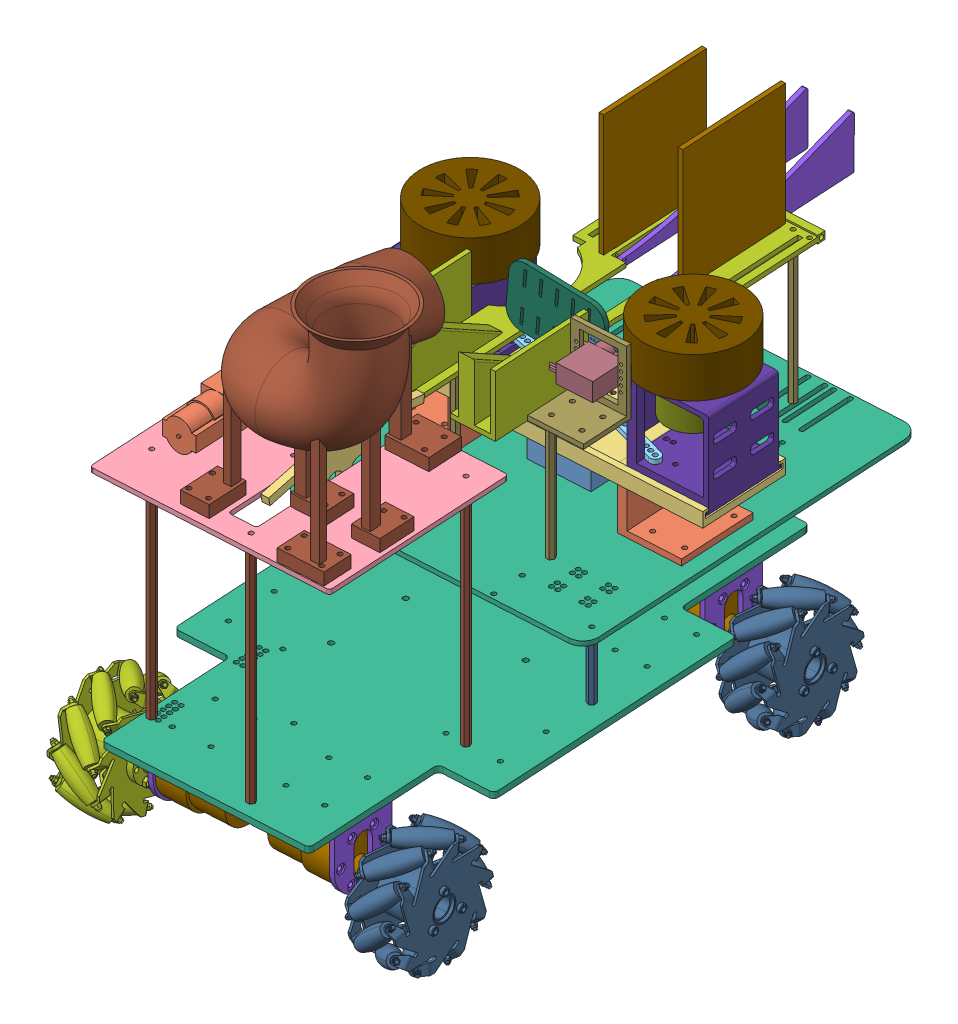
SolidWorks assembly 方案2完整, configuration 默认. Lengths in mm.
Overall size (245.27 390.99 446.91).
58 component instances, 32 part files, 89 mates.
Components (placement in the parent):
- 30kg大舵机-1: 30kg大舵机 [默认] at (-146.1932 -42.7359 104.9499) x (0.998416 0 -0.056268) z (0.056268 0 0.998416) size (54.5 44.5 20)
- 舵机固定架-1: 舵机固定架 [默认] at (-145.3492 -44.2359 119.9261) x (0.998416 0 -0.056268) z (0.056268 0 0.998416) size (180 36 50)
- 摩擦轮轨道-1: 摩擦轮轨道 [默认] at (-219.81 -12.6559 99.0829) x (0.998416 0 -0.056268) z (0.056268 0 0.998416) size (200 9.5 58)
- 摩擦轮传动舵盘-1: 摩擦轮传动舵盘 [默认] at (-135.444 -1.7359 94.3282) x (0.98502 0 0.17244) z (0 1 0) size (47 9.88 7.5)
- 摩擦轮传动杆-1: 摩擦轮传动杆 [默认] at (-175.5138 3.2641 86.9233) x (0.981614 0 0.190879) z (0 -1 0) size (48 7 3)
- 摩擦轮传动杆-2: 摩擦轮传动杆 [默认] at (-99.8398 3.2641 102.168) x (-0.963541 0 -0.26756) z (0 -1 0) size (48 7 3)
- 底板-麦轮装配体-1: 底板-麦轮装配体 [默认] at (149.5944 -56.9718 163.5191) x (0.056268 0 0.998416) z (-0.998416 0 0.056268) size (360.68 101.49 223.34)
  - 车底板-1: 车底板 [默认] at (-4.9651 -34.2642 350) size (350 4 200)
  - 75mecanumzuo-4: 75mecanumzuo [默认] at (-125.1754 -68.2642 364.1942) x (0.997346 -0.072807 0) z (-0.072807 -0.997346 0) size (77.38 50.5 75.94)
  - 电机支架-7: 电机支架 [默认] at (-145.2754 -37.4642 343.8942) x (1 0 0) z (0 1 0) size (40.2 43 47)
  - 新电机-1: 新电机 [默认] at (-125.1754 -61.2642 298.9942) x (-1 0 0) z (0 0 1) size (37 37 66.7)
  - 新电机-2: 新电机 [默认] at (-124.8754 -61.2642 272.0527) x (1 0 0) z (0 0 -1) size (37 37 66.7)
  - 电机支架-8: 电机支架 [默认] at (-104.7754 -37.4642 227.1527) x (-1 0 0) z (0 1 0) size (40.2 43 47)
  - 75mecanumyou-3: 75mecanumyou [默认] at (-124.8754 -68.2642 206.8527) x (0.923728 0.383049 0) z (-0.383049 0.923728 0) size (77.38 50.5 77.78)
  - 75mecanumzuo-6: 75mecanumzuo [默认] at (134.2366 -68.2642 364.1942) x (0.997346 -0.072807 0) z (-0.072807 -0.997346 0) size (77.38 50.5 75.94)
  - 新电机-3: 新电机 [默认] at (134.2366 -61.2642 298.9942) x (-1 0 0) z (0 0 1) size (37 37 66.7)
  - 电机支架-9: 电机支架 [默认] at (114.1366 -37.4642 343.8942) x (1 0 0) z (0 1 0) size (40.2 43 47)
  - 新电机-4: 新电机 [默认] at (134.5366 -61.2642 272.0527) x (1 0 0) z (0 0 -1) size (37 37 66.7)
  - 电机支架-10: 电机支架 [默认] at (154.6366 -37.4642 227.1527) x (-1 0 0) z (0 1 0) size (40.2 43 47)
  - 75mecanumyou-4: 75mecanumyou [默认] at (134.5366 -68.2642 206.8527) x (0.923728 0.383049 0) z (-0.383049 0.923728 0) size (77.38 50.5 77.78)
- 储弹管道-1: 储弹管道 [默认] at (-55.5513 137.7641 176.0746) x (0.056268 0 0.998416) z (-0.998416 0 0.056268) size (367.8 225.29 130.07)
- 40mm乒乓球-1: 40mm乒乓球 [默认] at (274.1004 235.7665 253.765) size (40 40 40) (hidden)
- 68mm网球-1: 68mm网球 [默认] at (387.195 229.0328 158.137) size (68 68 68) (hidden)
- mg90s舵机架-1: mg90s舵机架 [默认] at (-96.1146 50.7641 144.5432) x (-0.056268 0 -0.998416) z (0.998416 0 -0.056268) size (33 43 35)
- mg90s舵机-1: mg90s舵机 [默认] at (-78.164 79.6974 152.045) x (-0.998416 0 0.056268) z (0 -1 0) size (37.5 29 12)
- MG90S舵机臂-1: MG90S舵机臂 [默认] at (-84.8651 73.6974 130.8886) x (-0.994686 0.086351 0.056058) z (0.056268 0 0.998416) size (22 6.06 4)
- 弹道挡板-1: 弹道挡板 [默认] at (-118.7266 76.6334 132.0457) x (0.994686 -0.086351 -0.056058) z (-0.086214 -0.996265 0.004859) size (60 3 40)
- 3525电机和摩擦轮-1: 3525电机和摩擦轮 [默认] at (-175.4048 30.8362 96.7355) x (0 -1 0) z (-0.998416 0 0.056268) size (87.12 88.79 88.79)
  - 3525电机-1: 3525电机 [默认] at (4.9249 -1.155 36.6) size (36.6 35.3 35.3)
  - 3525电机固定支架-1: 3525电机固定支架 [默认] at (-17.4279 -1.155 36.6) x (0 -1 0) z (1 0 0) size (53 51 56.22)
  - 蓝色摩擦轮-1: 蓝色摩擦轮 [默认] at (-48.33 -1.155 36.6) x (0 -0.866025 -0.5) z (0 -0.5 0.866025) size (65 26.5 65)
  - 六角联轴器-1: 六角联轴器 [默认] at (-19.83 -1.155 36.6) x (0 0 1) z (-1 0 0) size (14 12.12 17)
- 3525电机和摩擦轮-2: 3525电机和摩擦轮 [默认] at (-108.5094 30.8362 91.6534) x (0 -1 0) z (0.998416 0 -0.056268) size (87.12 88.79 88.79)
  - 3525电机-1: 3525电机 [默认] at (4.9249 -1.155 36.6) size (36.6 35.3 35.3)
  - 3525电机固定支架-1: 3525电机固定支架 [默认] at (-17.4279 -1.155 36.6) x (0 -1 0) z (1 0 0) size (53 51 56.22)
  - 蓝色摩擦轮-1: 蓝色摩擦轮 [默认] at (-48.33 -1.155 36.6) x (0 -0.866025 -0.5) z (0 -0.5 0.866025) size (65 26.5 65)
  - 六角联轴器-1: 六角联轴器 [默认] at (-19.83 -1.155 36.6) x (0 0 1) z (-1 0 0) size (14 12.12 17)
- tt电机-1: tt电机 [默认] at (-178.7459 76.9141 263.1303) x (0 1 0) z (0.998416 0 -0.056268) size (22.3 70 34.8)
- 螺旋桨-1: 螺旋桨 [默认] at (-120.3207 76.9141 270.8551) x (-0.050533 0.439834 -0.896656) z (-0.998416 0 0.056268) size (108.77 108.8 23.05)
- 管道固定底板-1: 管道固定底板 [默认] at (-121.0819 65.7641 276.2549) x (0.056268 0 0.998416) z (0 -1 0) size (125 150 3)
- 5-5圆柱轴承-1: 5-5圆柱轴承 [默认] at (-167.8912 76.9141 273.536) x (0.005277 -0.995593 0.093626) z (0.05602 0.093775 0.994016) size (14 22 14)
- 弹射装置固定板-1: 弹射装置固定板 [默认] at (-142.9079 -47.2359 82.4057) x (-0.056268 0 -0.998416) z (0 1 0) size (234.46 189.43 3)
- 出射轨道底板可加挡板-1: 出射轨道底板可加挡板 [默认] at (-135.5775 50.7641 119.6712) x (-0.056268 0 -0.998416) z (0.998416 0 -0.056268) size (235.25 48.86 188.9)
- 出射斜面1-1: 出射斜面1 [默认] at (-157.0188 48.7368 23.5714) x (-0.056268 -0.00087 -0.998415) z (0.998416 0 -0.056268) size (130 34.64 3)
- 出射斜面1-2: 出射斜面1 [默认] at (-128.0648 48.7368 21.9396) x (-0.056268 -0.00087 -0.998415) z (0.998416 0 -0.056268) size (130 34.64 3)
- 出射挡板-1: 出射挡板 [默认] at (-165.6361 68.2924 25.2837) x (-0.056268 0 -0.998416) z (0.998416 0 -0.056268) size (72 87 3)
- 出射挡板-2: 出射挡板 [默认] at (-116.7176 68.2924 18.9045) x (0.056268 0 0.998416) z (-0.998416 0 0.056268) size (72 87 3)
- M3铜柱（40）-1: M3铜柱（40） [默认] at (-220.0987 -87.2359 188.6845) x (0.96885 0 0.24765) z (-0.24765 0 0.96885) size (5.3 40 4.7)
- M3铜柱（40）-2: M3铜柱（40） [默认] at (-190.9009 -87.2359 42.461) x (0.96885 0 0.24765) z (-0.24765 0 0.96885) size (5.3 40 4.7)
- M3铜柱（40）-3: M3铜柱（40） [默认] at (-103.7976 -87.2359 37.5521) x (0.96885 0 0.24765) z (-0.24765 0 0.96885) size (5.3 40 4.7)
- M3铜柱（40）-4: M3铜柱（40） [默认] at (-50.368 -87.2359 179.1189) x (0.926987 0 0.375094) z (-0.375094 0 0.926987) size (5.3 40 4.7)
- M3铜柱（150)-1: M3铜柱（150) [默认] at (-106.1404 -87.2359 347.8816) size (5.3 150 4.7)
- M3铜柱（150)-2: M3铜柱（150) [默认] at (-67.8932 -87.2359 244.5658) x (0.997575 0 0.069601) z (-0.069601 0 0.997575) size (5.3 150 4.7)
- M3铜柱（150)-3: M3铜柱（150) [默认] at (-186.9352 -87.2359 332.6537) x (0.999953 0 0.009678) z (-0.009678 0 0.999953) size (5.3 150 4.7)
- M3铜柱（95）-1: M3铜柱（95） [默认] at (-103.8085 -44.2359 152.7028) size (5.3 95 4.7)
- M3铜柱（95）-2: M3铜柱（95） [默认] at (-163.434 -44.2359 156.0631) x (0.94331 0 -0.331914) z (0.331914 0 0.94331) size (5.3 95 4.7)
- M3铜柱（95）-3: M3铜柱（95） [默认] at (-112.979 -44.2359 -16.1108) x (0.94331 0 -0.331914) z (0.331914 0 0.94331) size (5.3 95 4.7)
- M3铜柱（95）-4: M3铜柱（95） [默认] at (-173.2891 -44.2359 -12.7119) x (0.94331 0 -0.331914) z (0.331914 0 0.94331) size (5.3 95 4.7)
Mates (geometry in assembly coordinates):
- 同心1: concentric aligned: cylinder of 30kg大舵机-1 through (-171.758 -32.2359 91.3668) axis (0 1 0) radius 2.5; cylinder of 舵机固定架-1 through (-171.758 -44.2359 91.3668) axis (0 1 0) radius 2.5
- 同心2: concentric aligned: cylinder of 30kg大舵机-1 through (-171.1953 -32.2359 101.351) axis (0 1 0) radius 2.5; cylinder of 舵机固定架-1 through (-171.1953 -44.2359 101.351) axis (0 1 0) radius 2.5
- 同心5: concentric aligned: cylinder of 30kg大舵机-1 through (-122.3165 -32.2359 88.5804) axis (0 1 0) radius 2.5; cylinder of 舵机固定架-1 through (-122.3165 -44.2359 88.5804) axis (0 1 0) radius 2.5
- 重合3: coincident anti-aligned: plane of 30kg大舵机-1 through (-120.1117 -12.2359 83.4482) normal (0 1 0); plane of 舵机固定架-1 through (-198.0834 -12.2359 72.8187) normal (0 -1 0)
- 同心6: concentric anti-aligned: cylinder of 30kg大舵机-1 through (-135.444 1.7641 94.3282) axis (0 -1 0) radius 3; cylinder of 摩擦轮传动舵盘-1 through (-135.444 -1.7359 94.3282) axis (0 1 0) radius 3
- 重合11: coincident anti-aligned: plane of 30kg大舵机-1 through (-146.1932 -1.7359 104.9499) normal (0 1 0); plane of 摩擦轮传动舵盘-1 through (-135.444 -1.7359 94.3282) normal (0 -1 0)
- 重合14: coincident anti-aligned: plane of 摩擦轮传动舵盘-1 through (-158.2837 3.2641 92.6534) normal (0 -1 0); plane of 摩擦轮传动杆-1 through (-195.6369 3.2641 83.0102) normal (0 1 0)
- 重合15: coincident anti-aligned: plane of 摩擦轮传动舵盘-1 through (-158.2837 3.2641 92.6534) normal (0 -1 0); plane of 摩擦轮传动杆-2 through (-80.0873 3.2641 107.6529) normal (0 1 0)
- 同心12: concentric anti-aligned: cylinder of 摩擦轮传动舵盘-1 through (-155.3907 5.7641 90.8363) axis (0 -1 0) radius 1.25; cylinder of 摩擦轮传动杆-1 through (-155.3907 0.2641 90.8363) axis (0 1 0) radius 1.5
- 同心19: concentric aligned: cylinder of 舵机固定架-1 through (-160.6067 -44.2359 115.778) axis (0 1 0) radius 1.5; cylinder of 摩擦轮轨道-1 through (-160.6067 -12.6559 115.778) axis (0 1 0) radius 1.5
- 同心23: concentric anti-aligned: cylinder of mg90s舵机架-1 through (-92.6201 73.7641 144.3462) axis (0.056268 0 0.998416) radius 1; cylinder of mg90s舵机-1 through (-92.4513 73.7641 147.3415) axis (-0.056268 0 -0.998416) radius 0.9638
- 同心24: concentric anti-aligned: cylinder of mg90s舵机架-1 through (-64.6645 73.7641 142.7707) axis (0.056268 0 0.998416) radius 1; cylinder of mg90s舵机-1 through (-64.4957 73.7641 145.766) axis (-0.056268 0 -0.998416) radius 0.9638
- 重合26: coincident anti-aligned: plane of mg90s舵机架-1 through (-61.17 50.7641 142.5738) normal (-0.056268 0 -0.998416); plane of mg90s舵机-1 through (-90.1241 67.6974 144.2056) normal (0.056268 0 0.998416)
- 重合27: coincident anti-aligned: circle of mg90s舵机-1; cylinder of MG90S舵机臂-1 through (-84.8369 73.6974 131.3878) axis (0.056268 0 0.998416) radius 2.5
- 同心25: concentric anti-aligned: cylinder of MG90S舵机臂-1 through (-102.1455 75.2086 134.116) axis (-0.056268 0 -0.998416) radius 0.5; cylinder of 弹道挡板-1 through (-102.3143 75.2086 131.1208) axis (0.056268 0 0.998416) radius 0.5
- 重合29: coincident anti-aligned: plane of MG90S舵机臂-1 through (-101.7607 75.1654 132.0911) normal (-0.056268 0 -0.998416); plane of 弹道挡板-1 through (-101.7607 75.1654 132.0911) normal (0.056268 0 0.998416)
- 同心26: concentric anti-aligned: cylinder of MG90S舵机臂-1 through (-100.1561 75.0359 134.0039) axis (-0.056268 0 -0.998416) radius 0.5; cylinder of 弹道挡板-1 through (-100.3249 75.0359 131.0086) axis (0.056268 0 0.998416) radius 0.5
- 重合30: coincident anti-aligned: plane of mg90s舵机-1 through (-81.6447 73.6974 134.7134) normal (-0.056268 0 -0.998416); plane of MG90S舵机臂-1 through (-84.64 73.6974 134.8822) normal (0.056268 0 0.998416)
- 同心27: concentric aligned: cylinder of 舵机固定架-1 through (-132.905 -44.2359 74.1534) axis (0 1 0) radius 1.5; cylinder of 摩擦轮轨道-1 through (-132.905 -12.6559 74.1534) axis (0 1 0) radius 1.5
- 同心28: concentric aligned: cylinder of 舵机固定架-1 through (-140.8923 -44.2359 74.6035) axis (0 1 0) radius 1.5; cylinder of 摩擦轮轨道-1 through (-140.8923 -12.6559 74.6035) axis (0 1 0) radius 1.5
- 重合39: coincident anti-aligned: plane of 摩擦轮传动杆-1 through (-195.6369 0.2641 83.0102) normal (0 -1 0); plane of 3525电机和摩擦轮-1/3525电机固定支架-1 through (-212.0118 0.2641 97.6418) normal (0 1 0)
- 重合43: coincident anti-aligned: plane of 摩擦轮传动杆-2 through (-80.0873 0.2641 107.6529) normal (0 -1 0); plane of 3525电机和摩擦轮-2/3525电机固定支架-1 through (-71.9024 0.2641 90.7471) normal (0 1 0)
- 平行10: parallel anti-aligned: plane of 储弹管道-1 through (-115.7629 131.7641 316.1846) normal (-0.998416 0 0.056268); plane of 螺旋桨-1 through (-120.3207 76.9141 270.8551) normal (0.998416 0 -0.056268)
- 平行12: parallel anti-aligned: line of 摩擦轮轨道-1 through (-241.185 -4.9559 75.2478) axis (0.998416 0 -0.056268); line of 3525电机和摩擦轮-1/3525电机固定支架-1 through (-193.5064 -4.9559 70.5576) axis (-0.998416 0 0.056268)
- 平行13: parallel aligned: line of 摩擦轮轨道-1 through (-238.3716 -4.9559 125.1686) axis (0.998416 0 -0.056268); line of 3525电机和摩擦轮-2/3525电机固定支架-1 through (-93.39 -4.9559 64.9153) axis (0.998416 0 -0.056268)
- 同心36: concentric aligned: cylinder of 摩擦轮传动杆-1 through (-195.6369 0.2641 83.0102) axis (0 1 0) radius 1.5; cylinder of 3525电机和摩擦轮-1/3525电机固定支架-1 through (-195.6369 0.2641 83.0102) axis (0 1 0) radius 1.5
- 同心38: concentric aligned: cylinder of 摩擦轮传动杆-2 through (-88.2774 0.2641 105.3787) axis (0 1 0) radius 1.5; cylinder of 3525电机和摩擦轮-2/3525电机固定支架-1 through (-88.2774 0.2641 105.3787) axis (0 1 0) radius 1.5
- 重合55: coincident anti-aligned: line of 摩擦轮轨道-1 through (-241.2975 -4.9559 73.251) axis (0.998416 0 -0.056268); line of 3525电机和摩擦轮-1/3525电机固定支架-1 through (-193.5064 -4.9559 70.5576) axis (-0.998416 0 0.056268)
- 重合56: coincident aligned: line of 摩擦轮轨道-1 through (-241.2975 -4.9559 73.251) axis (0.998416 0 -0.056268); line of 3525电机和摩擦轮-2/3525电机固定支架-1 through (-93.39 -4.9559 64.9153) axis (0.998416 0 -0.056268)
- 平行14: parallel anti-aligned: plane of 底板-麦轮装配体-1/车底板-1 through (-200.1304 -87.2359 178.2559) normal (0 1 0); plane of 储弹管道-1 through (-55.5513 65.7641 176.0746) normal (0 -1 0)
- 平行15: parallel aligned: plane of 底板-麦轮装配体-1/车底板-1 through (-40.1432 -87.2359 93.9658) normal (0.998416 0 -0.056268); plane of 储弹管道-1 through (-53.832 65.7641 292.869) normal (0.998416 0 -0.056268)
- 重合61: coincident aligned: plane of 底板-麦轮装配体-1/车底板-1 through (-60.4693 -87.2359 355.3236) normal (0.056268 0 0.998416); plane of 管道固定底板-1 through (-147.5111 62.7641 360.229) normal (0.056268 0 0.998416)
- 平行20: parallel anti-aligned: plane of 底板-麦轮装配体-1/车底板-1 through (-200.1304 -87.2359 178.2559) normal (0 1 0); plane of 管道固定底板-1 through (-121.0819 62.7641 276.2549) normal (0 -1 0)
- 重合66: coincident anti-aligned: plane of 储弹管道-1 through (-55.5513 65.7641 176.0746) normal (0 -1 0); plane of 管道固定底板-1 through (-121.0819 65.7641 276.2549) normal (0 1 0)
- 平行22: parallel aligned: plane of 底板-麦轮装配体-1/车底板-1 through (-200.1304 -87.2359 178.2559) normal (0 1 0); plane of tt电机-1 through (-186.0209 88.0641 301.0998) normal (0 1 0)
- 同心47: concentric aligned: cylinder of 底板-麦轮装配体-1/车底板-1 through (-106.1404 -91.2359 347.8816) axis (0 1 0) radius 1.5; cylinder of 管道固定底板-1 through (-106.1404 62.7641 347.8816) axis (0 1 0) radius 1.5
- 同心48: concentric aligned: cylinder of 底板-麦轮装配体-1/车底板-1 through (-67.8932 -91.2359 244.5658) axis (0 1 0) radius 1.5; cylinder of 管道固定底板-1 through (-67.8932 62.7641 244.5658) axis (0 1 0) radius 1.5
- 平行24: parallel aligned: plane of 舵机固定架-1 through (-238.02 -44.2359 75.0695) normal (-0.998416 0 0.056268); plane of 底板-麦轮装配体-1/车底板-1 through (-230.2833 -87.2359 274.5507) normal (-0.998416 0 0.056268)
- 同心55: concentric aligned: cylinder of 储弹管道-1 through (-79.2614 73.7641 339.8264) axis (0 1 0) radius 1.5; cylinder of 管道固定底板-1 through (-79.261 62.7641 339.8264) axis (0 1 0) radius 1.5
- 同心56: concentric aligned: cylinder of 储弹管道-1 through (-56.9564 73.7641 338.5693) axis (0 1 0) radius 1.5; cylinder of 管道固定底板-1 through (-56.9564 62.7641 338.5693) axis (0 1 0) radius 1.5
- 距离1: distance = 3 mm anti-aligned: plane of 储弹管道-1 through (-125.7471 131.7641 316.7473) normal (0.998416 0 -0.056268); plane of 螺旋桨-1 through (-125.3128 76.9141 271.1364) normal (-0.998416 0 0.056268)
- 重合76: coincident anti-aligned: plane of tt电机-1 through (-186.0209 65.7641 301.0998) normal (0 -1 0); plane of 管道固定底板-1 through (-121.0819 65.7641 276.2549) normal (0 1 0)
- 同心57: concentric anti-aligned: circle of 螺旋桨-1; circle of 5-5圆柱轴承-1
- 同心58: concentric aligned: circle of tt电机-1; circle of 5-5圆柱轴承-1
- 同心68: concentric aligned: cylinder of 底板-麦轮装配体-1/车底板-1 through (-50.368 -91.2359 179.1189) axis (0 1 0) radius 1.5; cylinder of 弹射装置固定板-1 through (-50.368 -47.2359 179.1189) axis (0 1 0) radius 1.5
- 同心69: concentric aligned: cylinder of 底板-麦轮装配体-1/车底板-1 through (-220.0987 -91.2359 188.6845) axis (0 1 0) radius 1.5; cylinder of 弹射装置固定板-1 through (-220.0987 -47.2359 188.6845) axis (0 1 0) radius 1.5704
- 同心70: concentric anti-aligned: cylinder of 弹射装置固定板-1 through (-103.8085 -44.2359 152.7028) axis (0 -1 0) radius 1.5; cylinder of 出射轨道底板可加挡板-1 through (-103.8085 50.7641 152.7028) axis (0 1 0) radius 1.5
- 同心71: concentric aligned: circle of 弹射装置固定板-1; cylinder of 出射轨道底板可加挡板-1 through (-163.434 50.7641 156.0631) axis (0 1 0) radius 1.5
- 同心72: concentric aligned: cylinder of 舵机固定架-1 through (-230.6486 -44.2359 117.0072) axis (0 1 0) radius 1.5; cylinder of 弹射装置固定板-1 through (-230.6486 -47.2359 117.0072) axis (0 1 0) radius 1.5
- 重合88: coincident anti-aligned: plane of 舵机固定架-1 through (-198.0834 -44.2359 72.8187) normal (0 -1 0); plane of 弹射装置固定板-1 through (-142.9079 -44.2359 82.4057) normal (0 1 0)
- 同心73: concentric aligned: cylinder of mg90s舵机架-1 through (-86.703 50.7641 169.3639) axis (0 1 0) radius 1.5; cylinder of 弹射装置固定板-1 through (-86.703 -47.2359 169.3639) axis (0 1 0) radius 1.5
- 平行27: parallel aligned: plane of mg90s舵机架-1 through (-61.17 50.7641 142.5738) normal (0.998416 0 -0.056268); plane of 出射轨道底板可加挡板-1 through (-96.6415 90.7641 135.2096) normal (0.998416 0 -0.056268)
- 同心78: concentric anti-aligned: circle of 摩擦轮传动舵盘-1; circle of 摩擦轮传动杆-2
- 同心79: concentric anti-aligned: cylinder of 出射轨道底板可加挡板-1 through (-182.2115 52.2641 56.3996) axis (0.998416 0 -0.056268) radius 0.65; cylinder of 出射斜面1-2 through (-123.305 52.2641 53.0798) axis (-0.998416 0 0.056268) radius 0.5
- 同心81: concentric aligned: circle of 出射轨道底板可加挡板-1; cylinder of 出射斜面1-2 through (-127.4689 52.1997 -20.803) axis (-0.998416 0 0.056268) radius 1.5
- 重合92: coincident anti-aligned: plane of 出射轨道底板可加挡板-1 through (-127.0469 353.3432 -13.3148) normal (-0.998416 0 0.056268); plane of 出射斜面1-2 through (-126.8607 64.2748 -10.0113) normal (0.998416 0 -0.056268)
- 同心82: concentric anti-aligned: circle of 出射轨道底板可加挡板-1; cylinder of 出射斜面1-1 through (-152.2591 52.2641 54.7116) axis (-0.998416 0 0.056268) radius 0.5
- 同心83: concentric anti-aligned: circle of 出射轨道底板可加挡板-1; cylinder of 出射斜面1-1 through (-156.4229 52.1997 -19.1712) axis (-0.998416 0 0.056268) radius 1.5
- 重合94: coincident anti-aligned: plane of 出射轨道底板可加挡板-1 through (-158.9962 353.3432 -11.5143) normal (0.998416 0 -0.056268); plane of 出射斜面1-1 through (-158.81 64.2748 -8.2107) normal (-0.998416 0 0.056268)
- 重合96: coincident anti-aligned: plane of 出射轨道底板可加挡板-1 through (-121.5556 50.7641 -13.6243) normal (0.998416 0 -0.056268); plane of 出射挡板-2 through (-119.7128 68.2924 19.0733) normal (-0.998416 0 0.056268)
- 重合97: coincident anti-aligned: plane of 出射轨道底板可加挡板-1 through (-135.5775 53.7641 119.6712) normal (0 1 0); plane of 出射挡板-2 through (-121.2602 53.7641 -8.3831) normal (0 -1 0)
- 重合98: coincident anti-aligned: plane of 出射轨道底板可加挡板-1 through (-167.6824 50.7641 -11.0247) normal (0.998416 0 -0.056268); plane of 出射挡板-1 through (-165.6361 68.2924 25.2837) normal (-0.998416 0 0.056268)
- 重合99: coincident anti-aligned: plane of 出射轨道底板可加挡板-1 through (-135.5775 53.7641 119.6712) normal (0 1 0); plane of 出射挡板-1 through (-161.0935 53.7641 52.5713) normal (0 -1 0)
- 同心84: concentric aligned: circle of 弹射装置固定板-1; circle of M3铜柱（40）-1
- 重合100: coincident anti-aligned: plane of 弹射装置固定板-1 through (-142.9079 -47.2359 82.4057) normal (0 -1 0); plane of M3铜柱（40）-1 through (-220.0987 -47.2359 188.6845) normal (0 1 0)
- 重合101: coincident anti-aligned: plane of 底板-麦轮装配体-1/车底板-1 through (-200.1304 -87.2359 178.2559) normal (0 1 0); plane of M3铜柱（40）-1 through (-220.0987 -87.2359 188.6845) normal (0 -1 0)
- 同心85: concentric aligned: circle of 弹射装置固定板-1; circle of M3铜柱（40）-4
- 重合103: coincident anti-aligned: plane of 弹射装置固定板-1 through (-142.9079 -47.2359 82.4057) normal (0 -1 0); plane of M3铜柱（40）-4 through (-50.368 -47.2359 179.1189) normal (0 1 0)
- 同心86: concentric aligned: circle of 弹射装置固定板-1; circle of M3铜柱（40）-2
- 重合105: coincident anti-aligned: plane of 弹射装置固定板-1 through (-142.9079 -47.2359 82.4057) normal (0 -1 0); plane of M3铜柱（40）-2 through (-190.9009 -47.2359 42.461) normal (0 1 0)
- 同心87: concentric aligned: circle of 底板-麦轮装配体-1/车底板-1; circle of M3铜柱（40）-3
- 重合106: coincident anti-aligned: plane of 弹射装置固定板-1 through (-142.9079 -47.2359 82.4057) normal (0 -1 0); plane of M3铜柱（40）-3 through (-103.7976 -47.2359 37.5521) normal (0 1 0)
- 重合107: coincident aligned: plane of mg90s舵机架-1 through (-59.3132 50.7641 175.5215) normal (0 -1 0); plane of 出射轨道底板可加挡板-1 through (-135.5775 50.7641 119.6712) normal (0 -1 0)
- 同心88: concentric anti-aligned: circle of 管道固定底板-1; circle of M3铜柱（150)-1
- 重合109: coincident anti-aligned: plane of 管道固定底板-1 through (-121.0819 62.7641 276.2549) normal (0 -1 0); plane of M3铜柱（150)-1 through (-106.1404 62.7641 347.8816) normal (0 1 0)
- 重合110: coincident anti-aligned: plane of 底板-麦轮装配体-1/车底板-1 through (-200.1304 -87.2359 178.2559) normal (0 1 0); plane of M3铜柱（150)-1 through (-106.1404 -87.2359 347.8816) normal (0 -1 0)
- 同心89: concentric anti-aligned: circle of 管道固定底板-1; circle of M3铜柱（150)-2
- 重合112: coincident anti-aligned: plane of 管道固定底板-1 through (-121.0819 62.7641 276.2549) normal (0 -1 0); plane of M3铜柱（150)-2 through (-67.8932 62.7641 244.5658) normal (0 1 0)
- 同心90: concentric aligned: circle of 管道固定底板-1; circle of M3铜柱（150)-3
- 重合114: coincident anti-aligned: plane of 管道固定底板-1 through (-121.0819 62.7641 276.2549) normal (0 -1 0); plane of M3铜柱（150)-3 through (-186.9352 62.7641 332.6537) normal (0 1 0)
- 同心91: concentric aligned: circle of 出射轨道底板可加挡板-1; circle of M3铜柱（95）-1
- 重合116: coincident anti-aligned: plane of 出射轨道底板可加挡板-1 through (-135.5775 50.7641 119.6712) normal (0 -1 0); plane of M3铜柱（95）-1 through (-103.8085 50.7641 152.7028) normal (0 1 0)
- 重合117: coincident anti-aligned: plane of 弹射装置固定板-1 through (-142.9079 -44.2359 82.4057) normal (0 1 0); plane of M3铜柱（95）-1 through (-103.8085 -44.2359 152.7028) normal (0 -1 0)
- 同心92: concentric aligned: circle of 出射轨道底板可加挡板-1; circle of M3铜柱（95）-2
- 重合119: coincident anti-aligned: plane of 出射轨道底板可加挡板-1 through (-135.5775 50.7641 119.6712) normal (0 -1 0); plane of M3铜柱（95）-2 through (-163.434 50.7641 156.0631) normal (0 1 0)
- 同心93: concentric aligned: circle of 出射轨道底板可加挡板-1; circle of M3铜柱（95）-4
- 重合121: coincident anti-aligned: plane of 出射轨道底板可加挡板-1 through (-135.5775 50.7641 119.6712) normal (0 -1 0); plane of M3铜柱（95）-4 through (-173.2891 50.7641 -12.7119) normal (0 1 0)
- 同心94: concentric aligned: circle of 出射轨道底板可加挡板-1; circle of M3铜柱（95）-3
- 重合123: coincident anti-aligned: plane of 出射轨道底板可加挡板-1 through (-135.5775 50.7641 119.6712) normal (0 -1 0); plane of M3铜柱（95）-3 through (-112.979 50.7641 -16.1108) normal (0 1 0)
